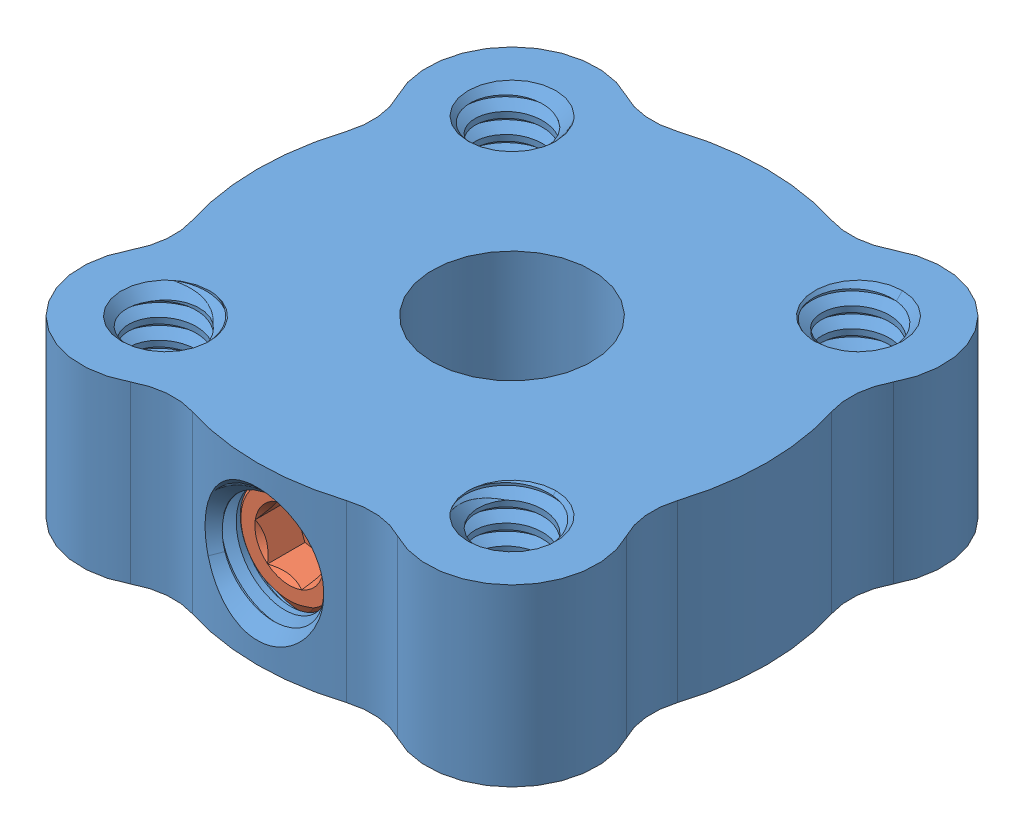
SolidWorks assembly Treadmill clamp 545548, configuration Default. Lengths in mm.
Overall size (21.08 13.19 21.37).
3 component instances, 3 part files, 1 mates.
Components (placement in the parent):
- 545548-1: 545548 [Default] at (-38.9112 12.0765 8.9709) size (20.57 9.63 20.57)
- 632138_91375A438-1: 632138_91375A438 [Default] at (-38.9112 18.109 15.0823) x (0.93363 0.358238 0) z (0 0 1) size (4.98 4.83 6.49)
- 6-32 Screw-1: 6-32 Screw [Default] at (-45.6425 24.1415 15.9952) x (-0.707107 0 -0.707107) z (0 1 0) size (5.74 5.74 13.19)
Mates (geometry in assembly coordinates):
- Coincident89: coincident anti-aligned: plane of 545548-1 through (-42.3686 14.6165 5.5135) normal (0 -1 0); circle of 6-32 Screw-1
